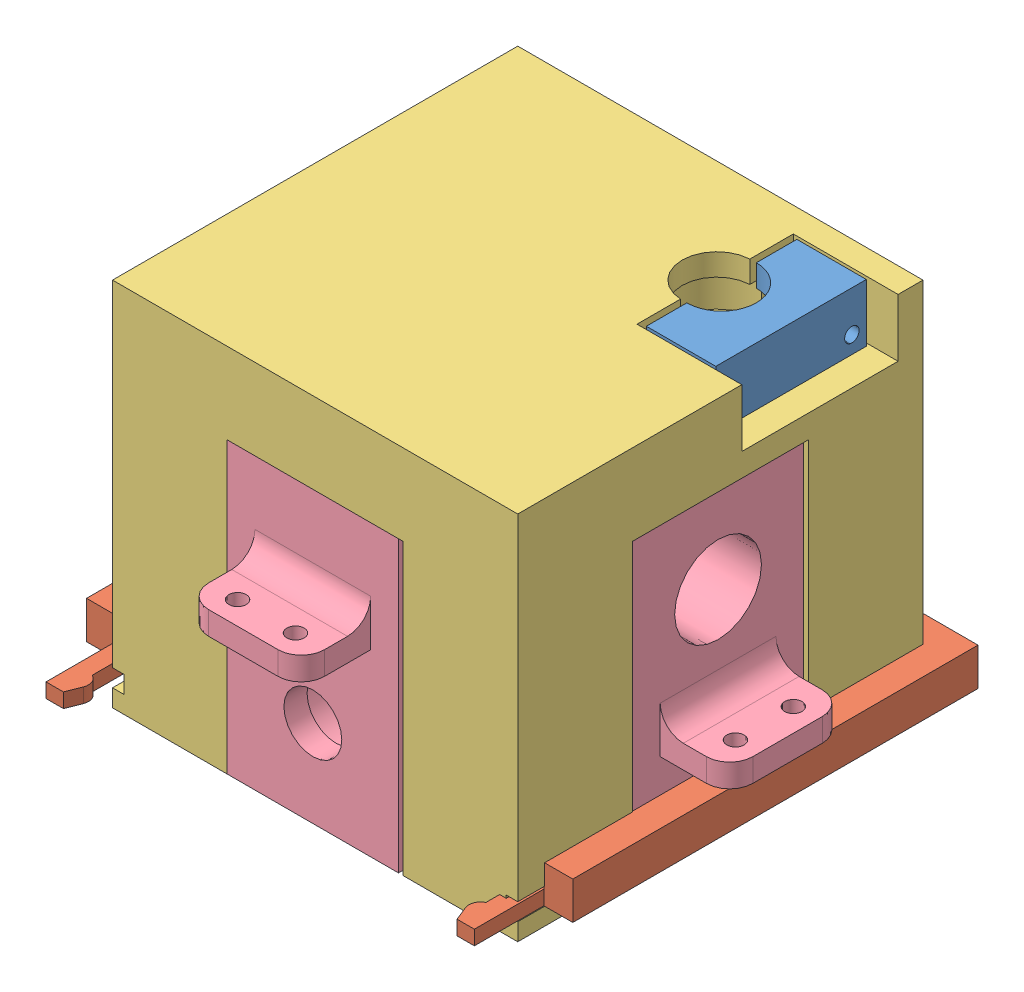
SolidWorks assembly P3DMIPC-Tête_complete, configuration Défaut. Lengths in mm.
Overall size (94 64.01 96.63).
4 component instances, 4 part files, 3 mates.
Components (placement in the parent):
- P3DMIPC-Clip_Buse_E3D-1: P3DMIPC-Clip_Buse_E3D [Défaut] at (17.0518 23.4109 40.0035) x (1 0 0) z (0 1 0) size (12 26 10)
- P3DMIPC-Clip_tête-1: P3DMIPC-Clip_tête [Défaut] at (26.9018 -25.0891 4.5597) x (1 0 0) z (0 -1 0) size (84 92 6.55)
- P3DMIPC-Porte_Buse_E3DX1-1: P3DMIPC-Porte_Buse_E3DX1 [Défaut] at (22.03 33.4019 79.1927) x (0 0 1) z (0 -1 0) size (70 70 64)
- P3DMIPC-Chariot-1: P3DMIPC-Chariot [Défaut] at (-48.37 -30.5981 79.1927) size (94 50 94)
Mates (geometry in assembly coordinates):
- Coïncidente19: coincident anti-aligned: plane of P3DMIPC-Porte_Buse_E3DX1-1 through (22.03 19.4019 79.1927) normal (0 -1 0); plane of P3DMIPC-Chariot-1 through (21.63 19.4019 79.1927) normal (0 1 0)
- Coïncidente20: coincident anti-aligned: plane of P3DMIPC-Porte_Buse_E3DX1-1 through (-28.17 19.4019 79.1927) normal (1 0 0); plane of P3DMIPC-Chariot-1 through (-28.17 19.4019 79.1927) normal (-1 0 0)
- Coïncidente21: coincident aligned: plane of P3DMIPC-Porte_Buse_E3DX1-1 through (22.03 -30.5981 79.1927) normal (0 0 1); plane of P3DMIPC-Chariot-1 through (21.63 -30.5981 79.1927) normal (0 0 1)
